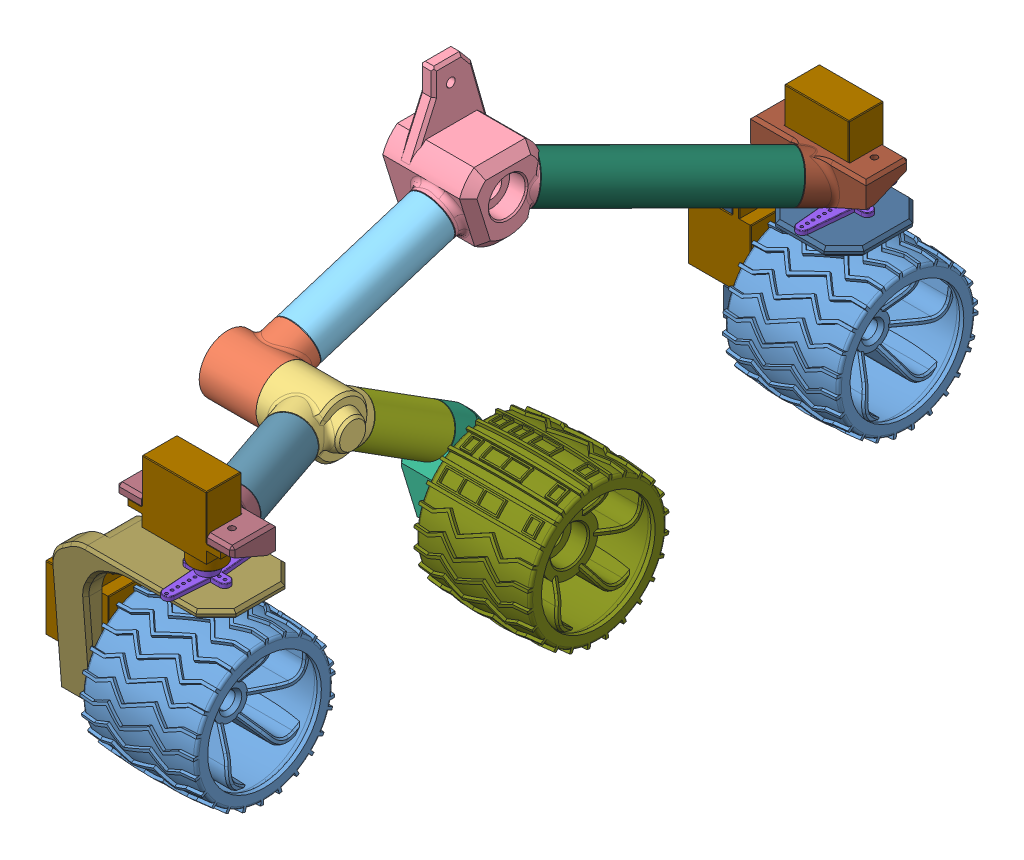
SolidWorks assembly suspensionSub-right, configuration Default. Lengths in mm.
Overall size (92.59 137.75 286.94).
24 component instances, 17 part files, 62 mates.
Components (placement in the parent):
- suspension3D-1: suspension3D [Default] at (24.2234 -21.993 143.476) size (85 93.78 276)
- tire-1: tire [Default] at (4.2234 -21.993 143.476) x (0 -0.999427 0.033856) z (1 0 0) size (53.45 55.85 40.12)
- tire-3: tire [Default] at (4.2234 -21.993 -82.524) x (0 -0.984808 0.173648) z (1 0 0) size (53.45 55.85 40.12)
- bogieJointFixed-right-1: bogieJointFixed-right [Default] at (-50.7766 18.817 81.456) x (0 0.297904 -0.954596) z (1 0 0) size (40 20 21.53)
- bogieJointFree-right-2: bogieJointFree-right [Default] at (-30.7766 18.817 81.456) x (1 0 0) z (0 0.534644 0.845077) size (27.04 27.37 57.25)
- rockerJoint-right-1: rockerJoint-right [Default] at (-58.2766 42.597 5.256) x (1 0 0) z (0 -0.297904 0.954596) size (35.64 50.55 55.79)
- aftRockerTube-1: aftRockerTube [Default] at (-40.7766 23.2868 67.1329) x (0.858574 -0.489411 -0.152732) z (0.512689 0.819591 0.255773) size (15.88 49.82 15.88)
- wheelStrut-mid-left-1: wheelStrut-mid-left [Default] at (-20.7766 -21.993 36.076) size (23.13 36.67 28.96)
- foreBogieTube-1: foreBogieTube [Default] at (-20.7766 -7.2198 40.3014) x (1 0 0) z (0 -0.845077 0.534644) size (15.88 33.7 15.88)
- sg90ServoHorn-star-1: sg90ServoHorn-star [Default] at (-15.7766 -23.893 -79.674) x (0 1 0) z (0 0 1) size (34.4 4 15.7)
- sg90Servo-1: sg90Servo [Default] at (-46.7446 -27.743 -88.674) x (0 1 0) z (0 0 -1) size (32.7 29.37 12.3)
- sg90ServoHorn-star-2: sg90ServoHorn-star [Default] at (-15.7766 -23.893 146.326) x (0 1 0) z (0 0 1) size (34.4 4 15.7)
- sg90Servo-2: sg90Servo [Default] at (-46.7446 -27.743 137.326) x (0 1 0) z (0 0 -1) size (32.7 29.37 12.3)
- wheelStrut-front-right-v2-1: wheelStrut-front-right-v2 [Default] at (-46.7446 -27.743 -88.674) x (0 1 0) z (0 0 -1) size (50.75 59.16 31.22)
- sg90ServoHorn-star-3: sg90ServoHorn-star [Default] at (7.0734 13.007 -80.624) x (0 0 -1) z (1 0 0) size (34.4 4 15.7)
- sg90Servo-3: sg90Servo [Default] at (9.9734 43.975 -76.374) x (-1 0 0) z (0 0 1) size (32.7 29.37 12.3)
- wheelPivot-front-right-v2-1: wheelPivot-front-right-v2 [Default] at (9.9734 43.975 -76.374) x (-1 0 0) z (0 0 1) size (40.7 16.47 34.17)
- wheelStrut-rear-right-v2-2: wheelStrut-rear-right-v2 [Default] at (-46.7446 -27.743 149.626) x (0 1 0) z (0 0 -1) size (50.75 59.16 31.22)
- sg90ServoHorn-star-4: sg90ServoHorn-star [Default] at (1.3734 13.007 141.576) x (0 0 1) z (-1 0 0) size (34.4 4 15.7)
- sg90Servo-4: sg90Servo [Default] at (9.9734 43.975 149.626) x (-1 0 0) z (0 0 1) size (32.7 29.37 12.3)
- wheelPivot-rear-right-v2-1: wheelPivot-rear-right-v2 [Default] at (9.9734 43.975 137.326) x (1 0 0) z (0 0 -1) size (40.7 18.75 35.49)
- aftBogieTube-1: aftBogieTube [Default] at (-15.1903 20.1331 95.3146) x (0.898204 -0.28457 -0.335037) z (-0.233519 -0.954631 0.184791) size (15.88 37.13 15.88)
- foreRockerTube-1: foreRockerTube [Default] at (-2.4655 24.4715 -69.4762) x (0.842254 0.427799 0.32802) z (0.302918 -0.878908 0.368458) size (15.88 70.91 15.88)
- tire-mid-1: tire-mid [Default] at (14.252 -21.993 36.076) x (0 0.377875 -0.925857) z (1 0 0) size (53.45 55.85 40.12)
Mates (geometry in assembly coordinates):
- Concentric1: concentric aligned: circle of tire-1; line of assembly
- Coincident1: coincident: point of suspension3D-1; plane of tire-1 through (-15.7766 -45.9768 144.2884) normal (-1 0 0)
- Concentric3: concentric aligned: circle of tire-3; line of assembly
- Coincident3: coincident: point of suspension3D-1; plane of tire-3 through (-15.7766 -45.626 -78.3569) normal (-1 0 0)
- Concentric4: concentric anti-aligned: circle of bogieJointFixed-right-1; line of assembly
- Concentric13: concentric aligned: line of suspension3D-1 through (-20.7766 18.817 81.456) axis (-1 0 0); cylinder of bogieJointFree-right-2 through (-10.7766 18.817 81.456) axis (-1 0 0) radius 10
- Concentric14: concentric aligned: line of suspension3D-1 through (4.2234 24.707 143.476) axis (-0.372423 -0.087743 -0.923906); cylinder of bogieJointFree-right-2 through (-15.1903 20.1331 95.3146) axis (-0.372423 -0.087743 -0.923906) radius 8
- Concentric15: concentric aligned: line of suspension3D-1 through (-40.7766 18.817 81.456) axis (0 0.297904 -0.954596); cylinder of rockerJoint-right-1 through (-40.7766 38.1284 19.5749) axis (0 0.297904 -0.954596) radius 8
- Concentric16: concentric anti-aligned: line of suspension3D-1 through (-40.7766 42.597 5.256) axis (0.445925 -0.210972 -0.869851); cylinder of rockerJoint-right-1 through (-34.0877 39.4324 -7.7918) axis (-0.445925 0.210972 0.869851) radius 8
- Concentric17: concentric anti-aligned: line of suspension3D-1 through (-40.7766 18.817 81.456) axis (0 0.297904 -0.954596); cylinder of bogieJointFixed-right-1 through (-40.7766 23.2855 67.137) axis (0 -0.297904 0.954596) radius 8
- Concentric18: concentric aligned: circle of rockerJoint-right-1; cylinder of aftRockerTube-1 through (-40.7766 38.1284 19.5749) axis (0 -0.297904 0.954596) radius 6.44
- Coincident20: coincident anti-aligned: plane of rockerJoint-right-1 through (-40.7766 38.1284 19.5749) normal (0 -0.297904 0.954596); plane of aftRockerTube-1 through (-40.7766 38.1284 19.5749) normal (0 0.297904 -0.954596)
- Concentric19: concentric aligned: line of suspension3D-1 through (-20.7766 18.817 81.456) axis (0 -0.534644 -0.845077); cylinder of wheelStrut-mid-left-1 through (-20.7766 -7.2198 40.3014) axis (0 -0.534644 -0.845077) radius 8
- Coincident27: coincident: line of suspension3D-1 through (-5.7766 -21.993 36.076) axis (-1 0 0); point of wheelStrut-mid-left-1
- Concentric20: concentric aligned: line of suspension3D-1 through (-20.7766 18.817 81.456) axis (0 -0.534644 -0.845077); cylinder of foreBogieTube-1 through (-20.7766 10.7977 68.7805) axis (0 -0.534644 -0.845077) radius 6.44
- Coincident29: coincident anti-aligned: plane of wheelStrut-mid-left-1 through (-20.7766 -7.2198 40.3014) normal (0 0.534644 0.845077); plane of foreBogieTube-1 through (-20.7766 -7.2198 40.3014) normal (0 -0.534644 -0.845077)
- Coincident54: coincident anti-aligned: plane of tire-3 through (-15.7766 -45.626 -78.3569) normal (-1 0 0); plane of sg90ServoHorn-star-1 through (-15.7766 -23.893 -79.674) normal (1 0 0)
- Concentric28: concentric aligned: line of suspension3D-1 through (24.2234 -21.993 -82.524) axis (-1 0 0); cylinder of sg90ServoHorn-star-1 through (-15.7756 -21.993 -82.524) axis (-1 0 0) radius 1.2
- Parallel14: parallel aligned: plane of sg90ServoHorn-star-1 through (-17.2366 -20.093 -79.674) normal (0 1 0); plane of assembly through (0 0 0) normal (0 1 0)
- Coincident57: coincident anti-aligned: plane of sg90ServoHorn-star-1 through (-17.3766 -21.993 -82.524) normal (-1 0 0); plane of sg90Servo-1 through (-17.3766 -21.993 -82.524) normal (1 0 0)
- Concentric29: concentric aligned: cylinder of sg90ServoHorn-star-1 through (-17.3766 -21.993 -82.524) axis (-1 0 0) radius 2.4; cylinder of sg90Servo-1 through (-17.3766 -21.993 -82.524) axis (-1 0 0) radius 1.984
- Parallel15: parallel anti-aligned: plane of sg90Servo-1 through (-24.5196 -27.743 -88.674) normal (0 0 -1); plane of assembly through (0 0 0) normal (0 0 1)
- Coincident59: coincident anti-aligned: plane of tire-1 through (-15.7766 -45.9768 144.2884) normal (-1 0 0); plane of sg90ServoHorn-star-2 through (-15.7766 -23.893 146.326) normal (1 0 0)
- Concentric33: concentric aligned: line of suspension3D-1 through (24.2234 -21.993 143.476) axis (-1 0 0); cylinder of sg90ServoHorn-star-2 through (-15.7756 -21.993 143.476) axis (-1 0 0) radius 1.2
- Parallel16: parallel aligned: plane of suspension3D-1 through (24.2234 -21.993 143.476) normal (0 1 0); plane of sg90ServoHorn-star-2 through (-17.2366 -20.093 146.326) normal (0 1 0)
- Coincident62: coincident anti-aligned: plane of sg90ServoHorn-star-2 through (-17.3766 -21.993 143.476) normal (-1 0 0); plane of sg90Servo-2 through (-17.3766 -21.993 143.476) normal (1 0 0)
- Concentric30: concentric aligned: cylinder of sg90ServoHorn-star-2 through (-17.3766 -21.993 143.476) axis (-1 0 0) radius 2.4; cylinder of sg90Servo-2 through (-17.3766 -21.993 143.476) axis (-1 0 0) radius 1.984
- Parallel17: parallel anti-aligned: plane of sg90Servo-2 through (-24.5196 -27.743 137.326) normal (0 0 -1); plane of assembly through (0 0 0) normal (0 0 1)
- InPlace1: in place: plane of ? through (-24.5196 -27.743 -88.674) normal (0 0 -1); plane of ? through (0 0 -88.674) normal (0 0 -1); moOrthogonalPlaneRef_w of ? through (-24.5196 -27.743 -88.674) normal (0 0 -1); unknown of ?; plane of ? through (-24.5196 -27.743 -88.674) normal (0 0 -1); plane of ? through (0 0 -88.674) normal (-1 0 0); plane of ? through (-24.5196 -27.743 -88.674) normal (0 0 -1); unknown of ?
- Coincident64: coincident aligned: plane of sg90Servo-1; plane of wheelStrut-front-right-v2-1
- Coincident65: coincident aligned: moOrthogonalPlaneRef_w of sg90Servo-1 through (-46.7446 -27.743 -88.674) normal (1 0 0); plane of wheelStrut-front-right-v2-1
- Coincident66: coincident anti-aligned: moOrthogonalPlaneRef_w of sg90Servo-1 through (-46.7446 -27.743 -88.674) normal (0 -1 0); plane of wheelStrut-front-right-v2-1
- Coincident67: coincident anti-aligned: plane of wheelStrut-front-right-v2-1 through (-46.7446 13.007 -95.674) normal (0 1 0); plane of sg90ServoHorn-star-3 through (7.0734 13.007 -80.624) normal (0 -1 0)
- Concentric31: concentric aligned: cylinder of wheelStrut-front-right-v2-1 through (4.2234 -37.7441 -82.524) axis (0 1 0) radius 2.4; cylinder of sg90ServoHorn-star-3 through (4.2234 13.006 -82.524) axis (0 1 0) radius 1.2
- Parallel18: parallel anti-aligned: plane of sg90ServoHorn-star-3 through (7.0734 14.467 -84.424) normal (0 0 -1); plane of wheelStrut-front-right-v2-1 through (-46.7446 -27.743 -64.374) normal (0 0 1)
- Coincident69: coincident anti-aligned: plane of sg90ServoHorn-star-3 through (4.2234 14.607 -82.524) normal (0 1 0); plane of sg90Servo-3 through (4.2234 14.607 -82.524) normal (0 -1 0)
- Concentric32: concentric aligned: cylinder of sg90ServoHorn-star-3 through (4.2234 14.607 -82.524) axis (0 1 0) radius 2.4; cylinder of sg90Servo-3 through (4.2234 14.607 -82.524) axis (0 1 0) radius 1.984
- Parallel19: parallel aligned: plane of wheelStrut-front-right-v2-1 through (-46.7446 -27.743 -64.374) normal (0 0 1); plane of sg90Servo-3 through (9.9734 21.75 -76.374) normal (0 0 1)
- InPlace2: in place: plane of ? through (9.9734 21.75 -76.374) normal (0 0 1); plane of ? through (0 0 -76.374) normal (0 0 1); plane of ? through (9.9734 21.75 -76.374) normal (0 0 1); plane of ? through (0 0 -76.374) normal (0 1 0); plane of ? through (9.9734 21.75 -76.374) normal (0 0 1); plane of ? through (0 0 -76.374) normal (1 0 0); plane of ? through (9.9734 21.75 -76.374) normal (0 0 1); unknown of ?
- Coincident70: coincident aligned: plane of sg90Servo-3; plane of wheelPivot-front-right-v2-1
- Coincident71: coincident aligned: moOrthogonalPlaneRef_w of sg90Servo-3 through (9.9734 43.975 -76.374) normal (0 -1 0); plane of wheelPivot-front-right-v2-1
- Coincident72: coincident anti-aligned: moOrthogonalPlaneRef_w of sg90Servo-3 through (9.9734 43.975 -76.374) normal (1 0 0); plane of wheelPivot-front-right-v2-1
- Coincident78: coincident anti-aligned: plane of sg90Servo-2 through (-24.5196 -27.743 149.626) normal (0 0 1); plane of wheelStrut-rear-right-v2-2 through (-46.7446 -27.743 149.626) normal (0 0 -1)
- Concentric34: concentric aligned: cylinder of wheelStrut-rear-right-v2-2 through (4.2234 -37.7441 143.476) axis (0 1 0) radius 2.4; cylinder of sg90ServoHorn-star-4 through (4.2234 13.006 143.476) axis (0 1 0) radius 1.2
- Coincident79: coincident anti-aligned: plane of wheelStrut-rear-right-v2-2 through (-46.7446 13.007 156.626) normal (0 1 0); plane of sg90ServoHorn-star-4 through (2.3234 13.007 146.326) normal (0 -1 0)
- Parallel22: parallel aligned: plane of wheelStrut-rear-right-v2-2 through (-46.7446 -27.743 125.326) normal (0 0 -1); plane of sg90ServoHorn-star-4 through (1.3734 14.467 141.576) normal (0 0 -1)
- Coincident81: coincident anti-aligned: plane of sg90ServoHorn-star-4 through (4.2234 14.607 143.476) normal (0 1 0); plane of sg90Servo-4 through (4.2234 14.607 143.476) normal (0 -1 0)
- Concentric35: concentric aligned: cylinder of sg90ServoHorn-star-4 through (4.2234 14.607 143.476) axis (0 1 0) radius 2.4; cylinder of sg90Servo-4 through (4.2234 14.607 143.476) axis (0 1 0) radius 1.984
- Coincident82: coincident aligned: plane of wheelStrut-rear-right-v2-2 through (-24.5196 -27.743 137.326) normal (0 0 -1); plane of sg90Servo-4 through (9.9734 21.75 137.326) normal (0 0 -1)
- InPlace3: in place: plane of sg90Servo-4 through (9.9734 21.75 137.326) normal (0 0 -1); plane of ? through (0 0 137.326) normal (0 0 -1); plane of sg90Servo-4 through (9.9734 21.75 137.326) normal (0 0 -1); unknown of ?; plane of sg90Servo-4 through (9.9734 21.75 137.326) normal (0 0 -1); plane of ? through (0 0 137.326) normal (-1 0 0); plane of sg90Servo-4 through (9.9734 21.75 137.326) normal (0 0 -1); unknown of wheelPivot-rear-right-v2-1
- Coincident83: coincident aligned: plane of sg90Servo-4; plane of wheelPivot-rear-right-v2-1
- Coincident84: coincident aligned: moOrthogonalPlaneRef_w of sg90Servo-4 through (9.9734 43.975 137.326) normal (0 -1 0); plane of wheelPivot-rear-right-v2-1 through (9.9734 43.975 137.326) normal (0 -1 0)
- Coincident85: coincident anti-aligned: moOrthogonalPlaneRef_w of sg90Servo-4 through (9.9734 43.975 137.326) normal (-1 0 0); plane of wheelPivot-rear-right-v2-1
- Concentric36: concentric aligned: cylinder of bogieJointFree-right-2 through (-15.1903 20.1331 95.3146) axis (-0.372423 -0.087743 -0.923906) radius 8; cylinder of aftBogieTube-1 through (-1.3622 23.391 129.6192) axis (-0.372423 -0.087743 -0.923906) radius 6.44
- Coincident86: coincident anti-aligned: plane of bogieJointFree-right-2 through (-15.1903 20.1331 95.3146) normal (0.372423 0.087743 0.923906); plane of aftBogieTube-1 through (-15.1903 20.1331 95.3146) normal (-0.372423 -0.087743 -0.923906)
- Concentric37: concentric aligned: cylinder of wheelPivot-front-right-v2-1 through (-2.4655 24.4715 -69.4762) axis (0.445925 -0.210972 -0.869851) radius 7.94; cylinder of foreRockerTube-1 through (-34.086 39.4316 -7.7951) axis (0.445925 -0.210972 -0.869851) radius 7.94
- Coincident87: coincident anti-aligned: plane of wheelPivot-front-right-v2-1 through (-2.4655 24.4715 -69.4762) normal (-0.445925 0.210972 0.869851); plane of foreRockerTube-1 through (-2.4655 24.4715 -69.4762) normal (0.445925 -0.210972 -0.869851)
- Coincident88: coincident aligned: line of sg90Servo-2 through (-31.1196 -4.793 137.576) axis (0 0 1); line of wheelStrut-rear-right-v2-2 through (-31.1196 -4.793 137.326) axis (0 0 1)
- Coincident89: coincident anti-aligned: line of sg90Servo-2 through (-31.1196 -27.993 149.376) axis (0 0 -1); line of wheelStrut-rear-right-v2-2 through (-31.1196 -27.993 137.326) axis (0 0 1)
- Concentric38: concentric aligned: line of suspension3D-1 through (34.2234 -21.993 36.076) axis (-1 0 0); cylinder of tire-mid-1 through (0.252 -21.993 36.076) axis (-1 0 0) radius 6.5
- Coincident93: coincident anti-aligned: plane of wheelStrut-mid-left-1 through (-5.748 -21.993 46.076) normal (1 0 0); plane of tire-mid-1 through (-5.748 -12.925 13.8577) normal (-1 0 0)
- Parallel23: parallel aligned: plane of tire-3 through (19.2234 -22.0349 -88.4329) normal (0 1 0); plane of sg90ServoHorn-star-1 through (-17.2366 -20.093 -79.674) normal (0 1 0)
